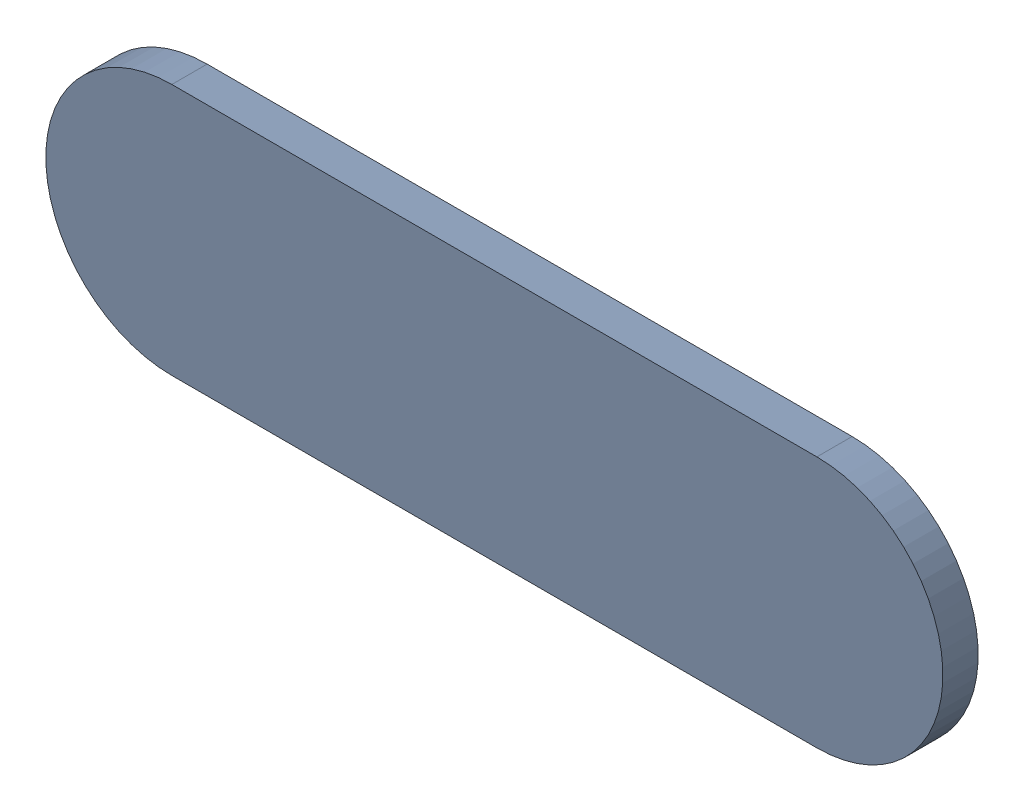
SolidWorks assembly Track (31mm,40mm)(31.65mm,40mm) on Top Layer, configuration Predeterminado. Lengths in mm.
Overall size (0.9 0.25 0.04).
2 component instances, 1 part files, 0 mates.
Components (placement in the parent):
- Track (31mm,40mm)(31.65mm,40mm) on Top Layer-1-1: Track (31mm,40mm)(31.65mm,40mm) on Top Layer-1 [Predeterminado] at (-68.317 -44.187 -0.0457) size (0.9 0.25 0.04)
  - Track (31mm,40mm)(31.65mm,40mm) on Top Layer-Part-1-1: Track (31mm,40mm)(31.65mm,40mm) on Top Layer-Part-1 [Predeterminado] at origin size (0.9 0.25 0.04)
